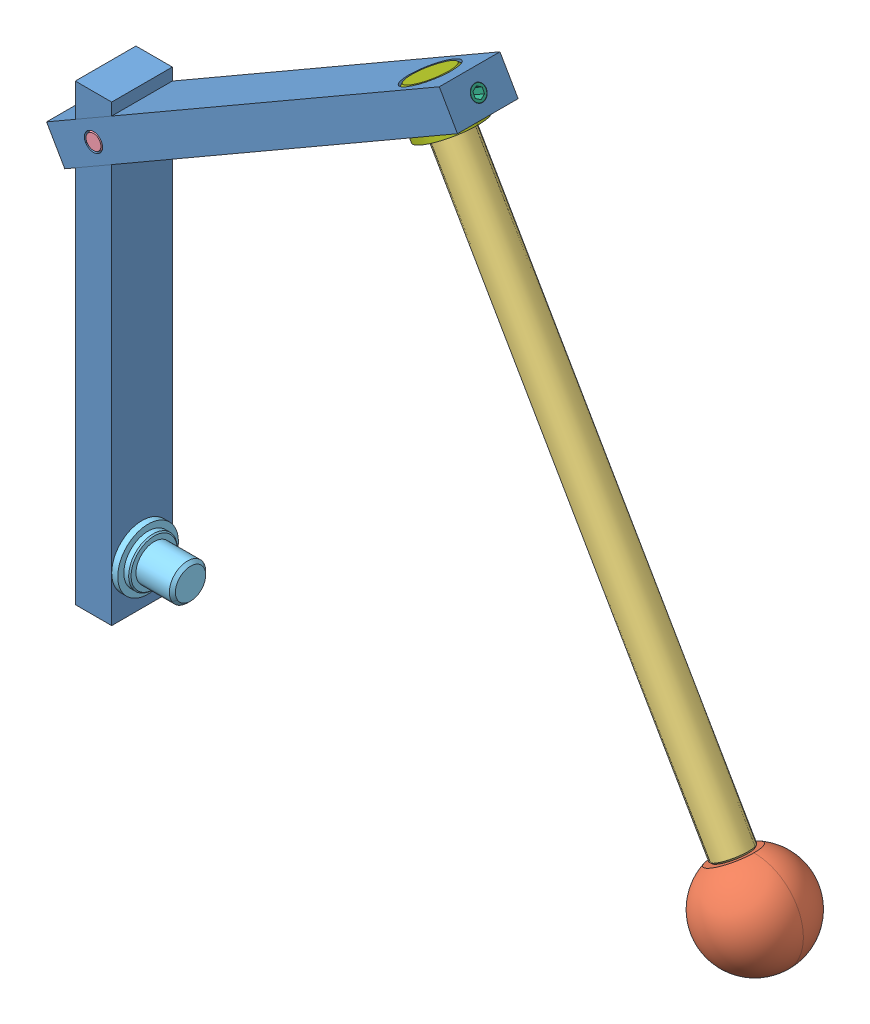
SolidWorks assembly 110303047-64, configuration 預設. Lengths in mm.
Overall size (122.66 107.34 16).
9 component instances, 7 part files, 15 mates.
Components (placement in the parent):
- long_link_section-1: long_link_section [預設] at (87.955 -29.8703 74.7406) x (0 1 0) z (0 0 1) size (74.74 6 10)
- long_link_section-2: long_link_section [預設] at (87.955 -29.8703 74.7406) x (-0.866025 -0.5 0) z (0 0 -1) size (74.74 6 10)
- ALBC16-1: ALBC16 [預設] at (87.955 -29.8703 74.7406) x (0.866025 0.5 0) z (0 0 1) size (16 15 16)
- SSFR6-93-M5-N6-1: SSFR6-93-M5-N6 [預設] at (34.955 61.9284 74.7406) x (-0.72501 -0.418585 -0.546944) z (-0.473668 -0.273472 0.837169) size (6 104 6)
- MSCSS3-10-1: MSCSS3-10 [預設] at (-16.045 30.1742 74.7406) x (0 0 1) z (-1 0 0) size (10 3 3)
- revolute_joint-1: revolute_joint [預設] at (-19.045 -29.8703 74.7406) x (0 0.858051 0.513564) z (0 0.513564 -0.858051) size (10 14 10)
- MSSFS3-4-1: MSSFS3-4 [預設] at (-16.045 -35.3703 74.7406) x (0 1 0) z (0 0 1) size (4 3 3)
- MSSFS3-4-2: MSSFS3-4 [預設] at (40.7181 62.9464 74.7406) x (-0.866025 -0.5 0) z (-0.021999 0.038104 0.999032) size (4 3 3)
- shaft_housing_axis-1: shaft_housing_axis [預設] at (34.455 62.7944 74.7406) x (-0.866025 -0.5 0) z (0 0 1) size (10 7 10)
Mates (geometry in assembly coordinates):
- 重合/共線/共點1: coincident anti-aligned: plane of long_link_section-1 through (87.955 -29.8703 74.7406) normal (0 0 1); plane of long_link_section-2 through (87.955 -29.8703 74.7406) normal (0 0 -1)
- 重合/共線/共點2: coincident anti-aligned: plane of long_link_section-1 through (-19.045 -37.3703 79.7406) normal (-1 0 0); plane of long_link_section-2 through (-19.045 31.9062 69.7406) normal (1 0 0)
- 重合/共線/共點3: coincident anti-aligned: plane of long_link_section-1 through (-19.045 31.9062 79.7406) normal (0.5 -0.866025 0); plane of long_link_section-2 through (40.9502 66.5444 69.7406) normal (-0.5 0.866025 0)
- 同軸心1: concentric anti-aligned: cylinder of long_link_section-2 through (-16.045 30.1742 79.7406) axis (0 0 -1) radius 1.5; cylinder of MSCSS3-10-1 through (-16.045 30.1742 79.7406) axis (0 0 1) radius 1.5
- 重合/共線/共點4: coincident aligned: plane of long_link_section-2 through (87.955 -29.8703 79.7406) normal (0 0 1); plane of MSCSS3-10-1 through (-16.045 31.4062 79.7406) normal (0 0 1)
- 同軸心3: concentric anti-aligned: cylinder of long_link_section-1 through (-13.045 -29.8703 74.7406) axis (-1 0 0) radius 4; cylinder of revolute_joint-1 through (-19.045 -29.8703 74.7406) axis (1 0 0) radius 4
- 重合/共線/共點6: coincident aligned: plane of long_link_section-1 through (-13.045 -37.3703 79.7406) normal (1 0 0); circle of revolute_joint-1
- 同軸心4: concentric anti-aligned: cylinder of long_link_section-2 through (37.455 57.5983 74.7406) axis (-0.5 0.866025 0) radius 4; cylinder of shaft_housing_axis-1 through (34.455 62.7944 74.7406) axis (0.5 -0.866025 0) radius 4
- 重合/共線/共點7: coincident anti-aligned: plane of long_link_section-2 through (43.9502 61.3483 69.7406) normal (0.5 -0.866025 0); plane of shaft_housing_axis-1 through (41.7851 60.0983 74.7406) normal (-0.5 0.866025 0)
- 同軸心7: concentric anti-aligned: cylinder of ALBC16-1 through (84.455 -23.8081 74.7406) axis (-0.5 0.866025 0) radius 1.65; cylinder of SSFR6-93-M5-N6-1 through (34.955 61.9284 74.7406) axis (0.5 -0.866025 0) radius 2
- 重合/共線/共點8: coincident anti-aligned: plane of ALBC16-1 through (81.1009 -25.7446 74.7406) normal (-0.5 0.866025 0); plane of SSFR6-93-M5-N6-1 through (85.905 -22.9709 75.8345) normal (0.5 -0.866025 0)
- 同軸心8: concentric aligned: cylinder of SSFR6-93-M5-N6-1 through (34.955 61.9284 74.7406) axis (0.5 -0.866025 0) radius 2; cylinder of shaft_housing_axis-1 through (37.955 56.7323 74.7406) axis (0.5 -0.866025 0) radius 1.65
- 重合/共線/共點9: coincident anti-aligned: plane of SSFR6-93-M5-N6-1 through (40.13 57.988 76.3814) normal (-0.5 0.866025 0); plane of shaft_housing_axis-1 through (37.955 56.7323 74.7406) normal (0.5 -0.866025 0)
- 輪廓中心1: profile center anti-aligned: plane of long_link_section-2 through (43.9502 61.3483 69.7406) normal (0.866025 0.5 0); circle of MSSFS3-4-2
- 輪廓中心2: profile center anti-aligned: plane of long_link_section-1 through (-13.045 -37.3703 79.7406) normal (0 -1 0); circle of MSSFS3-4-1
